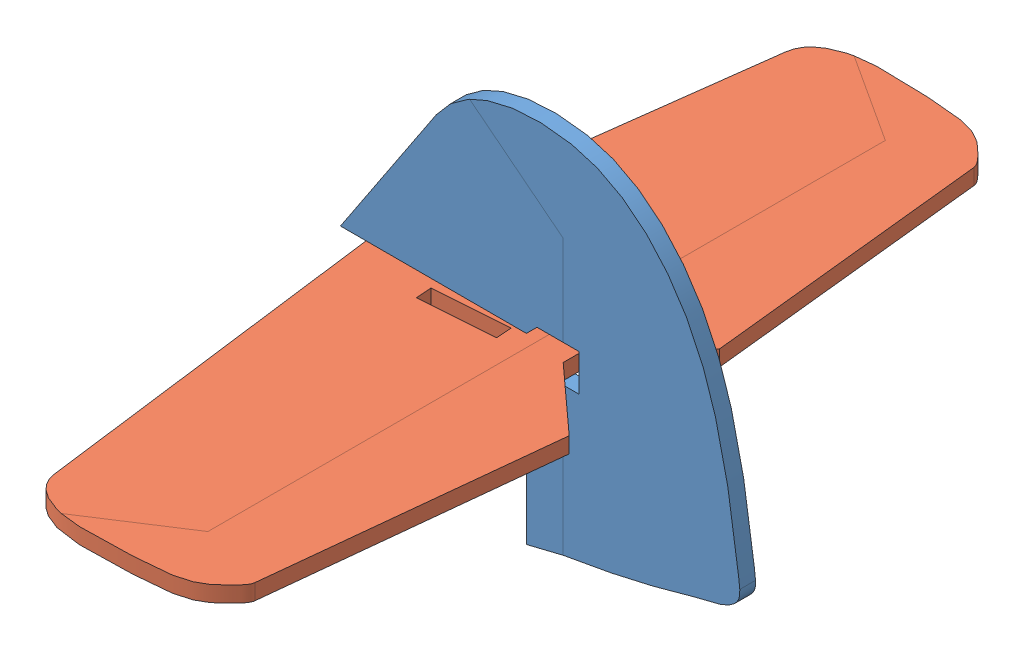
SolidWorks assembly BF109_Tail, configuration Default. Lengths in mm.
Overall size (135.74 127.69 270.43).
2 component instances, 2 part files, 3 mates.
Components (placement in the parent):
- BF109_Rudder-1: BF109_Rudder [Default] at origin size (135.74 127.69 5.33)
- BF109_Elevator-1: BF109_Elevator [Default] at (10.9958 -1.327 0) size (91.95 5.33 270.43)
Mates (geometry in assembly coordinates):
- Coincident1: coincident aligned: plane of BF109_Elevator-1 through (10.9958 -1.327 0) normal (0 0 1); plane of assembly through (0 0 0) normal (0 0 1)
- Coincident2: coincident anti-aligned: plane of BF109_Rudder-1 through (0 4.007 2.667) normal (0 -1 0); plane of BF109_Elevator-1 through (10.9958 4.007 0) normal (0 1 0)
- Distance1: distance = 10.9958 mm aligned: plane of BF109_Elevator-1 through (10.9958 -1.327 0) normal (1 0 0); plane of BF109_Rudder-1 through (0 0 0) normal (1 0 0)
